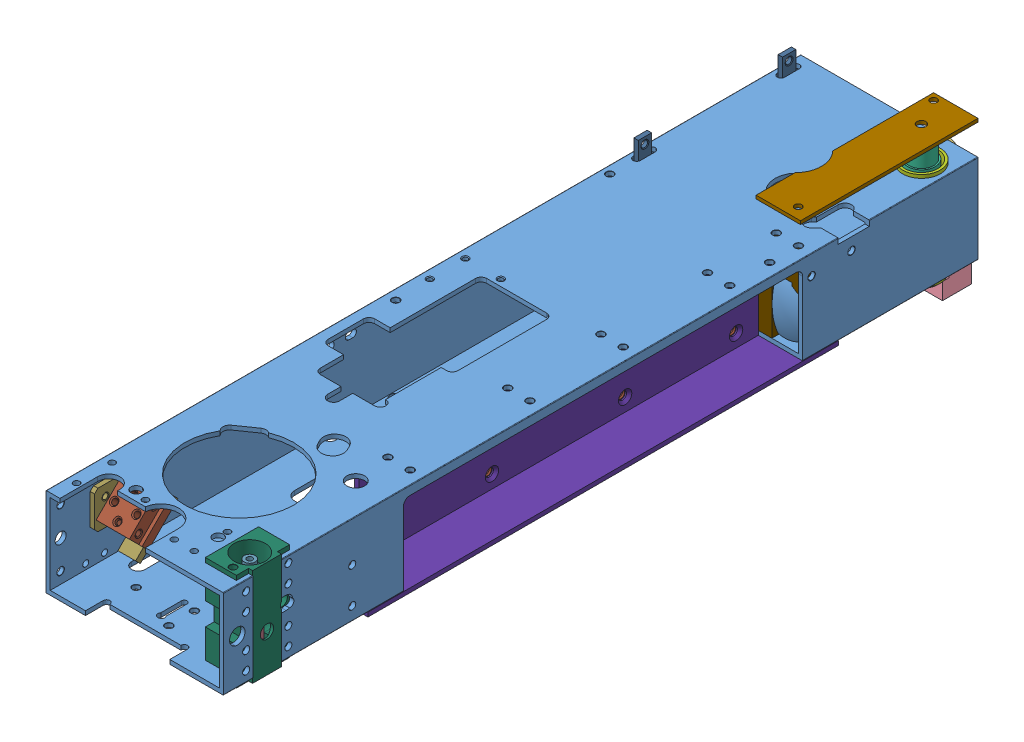
SolidWorks assembly База, configuration По умолчанию. Lengths in mm.
Overall size (100 66.2 347).
43 component instances, 32 part files, 69 mates.
Components (placement in the parent):
- короб_омб-1: короб_омб [v2] at origin size (80 40 340)
- призма_в_оправе_выходная-1: призма_в_оправе_выходная [По умолчанию] at (36.6 -18.1 -39) x (-1 0 0) z (0 0 -1) size (25.01 33.43 44.8)
  - оправа_призмы-1: оправа_призмы [Default] at (-1.5 0 6) size (25 25 36)
  - 9510170000040-1: 9510170000040 [По умолчанию] at (9.8225 13.066 21.9) x (-1 0 0) z (0 0 1) size (21.19 20 15.9)
    - 9510170000041-1: 9510170000041 [По умолчанию] at (-11.1761 -9.434 0) size (21.01 20 15.9)
    - 9510170000042-3: 9510170000042 [По умолчанию] at (-11.1775 -9.434 0.0019) size (11.8 20 15.69)
  - Линза_люк_левый-1: Линза_люк_левый [По умолчанию] at (4.5 13 38.5) x (1 0 0) z (0 -1 0) size (17 3.5 21) (hidden)
  - зеркало_11х25-1: зеркало_11х25 [Default] at (5.0962 13 26.2739) x (0 1 0) z (-0.707107 0 -0.707107) size (25 11 3)
  - зеркало_11х25-2: зеркало_11х25 [Default] at (16.9038 13 26.4588) x (0 1 0) z (0.707107 0 0.707107) size (25 11 3)
  - люк_левый_v4-1: люк_левый_v4 [По умолчанию] at (11 12.5 32.5) size (21 21 9.5)
  - Плата_с_датчиками_1-1: Плата_с_датчиками_1 [По умолчанию] at (14.5 32 -5.4093) x (-1 0 0) z (0 0 -1) size (16 6.63 32)
    - плата_датчиков_1-1: плата_датчиков_1 [По умолчанию] at origin size (16 1 32)
    - EE-SX1106-1: EE-SX1106 [По умолчанию] at (15.85 0 -10.6093) x (0 0 -1) z (0 1 0) size (8.9 4.2 6.63)
    - EE-SX1106-2: EE-SX1106 [По умолчанию] at (4.4 0 -8.6093) x (0 0 -1) z (0 1 0) size (8.9 4.2 6.63)
  - шторка_v4-1: шторка_v4 [По умолчанию] at (0.6402 3 5.3629) x (0.983937 0 -0.178516) z (0 -1 0) size (11 33.93 26.5)
- КРОНШТЕЙН5Ю-2: КРОНШТЕЙН5Ю [По умолчанию] at (-28.6 -2.8602 -33.8891) x (-1 0 0) z (0 0.707107 0.707107) size (15 16 13.5)
- зеркало_8х24-1: зеркало_8х24 [По умолчанию] at (34.1 -7.3 -29.7895) x (0 -0.707107 0.707107) z (0 0.707107 0.707107) size (24 8 3)
- зеркало_8х24-2: зеркало_8х24 [По умолчанию] at (-13.1 -7.9175 -31.6602) x (0 -0.707107 0.707107) z (0 0.707107 0.707107) size (24 8 3)
- зеркало_9х22-1: зеркало_9х22 [Default] at (32.1 -1.5 -19.7) x (0 -1 0) z (0.707107 0 0.707107) size (22 9 3)
- Бобышка зеркала-1: Бобышка зеркала [По умолчанию] at (32.1 19.5 -19.7) x (0.707107 0 -0.707107) z (0.707107 0 0.707107) size (10 17 10)
- экран_ФЭУ_2-1: экран_ФЭУ_2 [Default] at (32.1 -22 -19.7) x (0 0 -1) z (1 0 0) size (24 44.13 15.8)
- КРОНШТЕЙН9Ю-2: КРОНШТЕЙН9Ю [Default] at (24.6 11.5355 -25.9976) x (-1 0 0) z (0 1 0) size (10 14.51 12)
- отсек_кюветы_v3-1: отсек_кюветы_v3 [По умолчанию] at (18.1 -1.9 -277) x (0 -1 0) z (0 0 1) size (40 22 212)
- люк_правый_с_линзой-1: люк_правый_с_линзой [По умолчанию] at (38.1 -18.1 -261) x (-1 0 0) z (0 0 -1) size (24 36.25 8)
  - люк_правый_v3-1: люк_правый_v3 [По умолчанию] at origin size (24 36.25 8)
  - Линза_люк_правый-1: Линза_люк_правый [По умолчанию] at (9 13.25 8) x (-1 0 0) z (0 -1 0) size (12 5 26)
- подвес-1: подвес [По умолчанию] at (-3.1 -18.1 -340) size (30 36.2 8)
- шар-1: шар [По умолчанию] at (17.9 5.1 -344) x (0 1 0) z (0 0 1) size (20 20 7)
- Подвес_кюветы-1: Подвес_кюветы [По умолчанию] at (37 -20 -327) x (-1 0 0) z (0 0 1) size (77 11 13)
- вкладыш_3-1: вкладыш_3 [По умолчанию] at (-38.1 -18.1 -340) size (10 18 10)
- R6354-1: R6354 [По умолчанию] at (23.6045 21.0452 -325) x (-0.258819 0 0.965926) z (0 -1 0) size (82.45 40.02 58.7)
  - E678-11U-1: E678-11U [Default] at (-1.5259 -5.6946 -0.6548) x (0 -1 0) z (0 0 1) size (12.4 12.4 10.1)
  - ГА25301030090_ver_1-1: ГА25301030090_ver_1 [Default] at (-1.5259 -5.6946 44.5452) x (0.965926 -0.258819 0) z (0 0 1) size (17 17 45)
  - катод-1: катод [По умолчанию] at (1.8549 -6.6005 25.9452) x (0.258819 0.965926 0) z (0.965926 -0.258819 0) size (11 25 0.5)
  - плата_ФЭУ-1: плата_ФЭУ [По умолчанию] at (-18.7324 -11.9546 -14.1548) x (0.965926 -0.258819 0) z (-0.258819 -0.965926 0) size (80 1.5 20)
- планка_2хМ3_1-1: планка_2хМ3_1 [По умолчанию] at (-36.1 20 -331) x (-1 0 0) z (0 -1 0) size (2.18 6 14)
- планка_2хМ3_1-2: планка_2хМ3_1 [По умолчанию] at (-36.1 20 -266) x (-1 0 0) z (0 -1 0) size (2.18 6 14)
- планка_180-1: планка_180 [По умолчанию] at (18 -18.1 -81) x (-1 0 0) z (0 0 -1) size (9 7 180)
- катод-1: катод [По умолчанию] at (31.4671 -4.8343 -19.6845) x (0 0 1) z (-1 0 0) size (11 25 0.5) (suppressed, hidden)
- пластина_16х16-1: пластина_16х16 [По умолчанию] at (-36.1 -3.97 -35) x (0 0 1) z (-1 0 0) size (17 17 2)
- подкрепление-1: подкрепление [По умолчанию] at (-2.9 12.6 -29) (suppressed, hidden)
- втулка_2-1: втулка_2 [По умолчанию] at (8.1 -21 -80.5) x (1 0 0) z (0 -1 0) size (16 16 7.8)
- втулка_2-2: втулка_2 [По умолчанию] at (15.1 -21 -286) x (1 0 0) z (0 -1 0) size (16 16 7.8)
Mates (geometry in assembly coordinates):
- Угол2: planar angle = 3.926991 rad anti-aligned: plane of КРОНШТЕЙН5Ю-2 through (-21.1 12.3426 -30) normal (0 0.707107 0.707107); plane of короб_омб-1 through (-40 20 0) normal (0 0 1)
- Совпадение6: coincident anti-aligned: plane of зеркало_8х24-2 through (-31.6 -11.3454 -23.9896) normal (0 0.707107 0.707107); plane of КРОНШТЕЙН5Ю-2 through (-17.8791 3.5038 -38.8388) normal (0 -0.707107 -0.707107)
- Расстояние2: distance = 5 mm aligned: plane of зеркало_8х24-2 through (-31.6 -11.3454 -23.9896) normal (0 -0.707107 0.707107); plane of КРОНШТЕЙН5Ю-2 through (-21.1 1.0289 -18.6863) normal (0 -0.707107 0.707107)
- Расстояние14: distance = 0 mm anti-aligned: plane of короб_омб-1 through (-38.1 -18.1 -340) normal (0 1 0); plane of призма_в_оправе_выходная-1/оправа_призмы-1 through (13.1 -18.1 -81) normal (0 -1 0)
- Расстояние10: distance = 0 mm anti-aligned: plane of короб_омб-1 through (38.1 -18.1 -340) normal (-1 0 0); plane of призма_в_оправе_выходная-1/оправа_призмы-1 through (38.1 -18.1 -81) normal (1 0 0)
- Совпадение48: coincident anti-aligned: plane of зеркало_9х22-1 through (31.0393 9.5 -14.3967) normal (0 1 0); plane of Бобышка зеркала-1 through (24.2218 9.5 -27.5782) normal (0 -1 0)
- Совпадение46: coincident anti-aligned: plane of зеркало_9х22-1 through (35.282 9.5 -22.882) normal (-0.707107 0 -0.707107); plane of Бобышка зеркала-1 through (32.1 9.5 -19.7) normal (0.707107 0 0.707107)
- Расстояние15: distance = 0 mm aligned: plane of короб_омб-1 through (18 0 -81) normal (0 0 -1); plane of призма_в_оправе_выходная-1/оправа_призмы-1 through (38.1 -18.1 -81) normal (0 0 -1)
- Расстояние195: distance = 2 mm anti-aligned: plane of короб_омб-1 through (-38.1 -18.1 -340) normal (1 0 0); plane of КРОНШТЕЙН5Ю-2 through (-36.1 1.0289 -18.6863) normal (-1 0 0)
- Расстояние17: distance = 0.5 mm aligned: plane of зеркало_9х22-1 through (31.0393 9.5 -14.3967) normal (-0.707107 0 0.707107); cylinder of Бобышка зеркала-1 through (32.1 19.5 -19.7) axis (0 1 0) radius 5
- Ширина3: width aligned: plane of зеркало_8х24-2 through (-23.6 -11.3454 -23.9896) normal (1 0 0); plane of зеркало_8х24-2 through (-31.6 -11.3454 -23.9896) normal (-1 0 0); plane of КРОНШТЕЙН5Ю-2 through (-23.6 4.2109 -38.1317) normal (-1 0 0); plane of КРОНШТЕЙН5Ю-2 through (-31.6 4.2109 -38.1317) normal (1 0 0)
- Угол3: planar angle = 0.785398 rad aligned: plane of Бобышка зеркала-1 through (32.1 9.5 -19.7) normal (0.707107 0 0.707107); plane of короб_омб-1 through (-40 20 0) normal (0 0 1)
- Совпадение384: coincident anti-aligned: plane of короб_омб-1 through (38.1 -18.1 -340) normal (-1 0 0); plane of экран_ФЭУ_2-1 through (38.1 22 -7.7) normal (1 0 0)
- Расстояние194: distance = 2 mm aligned: plane of экран_ФЭУ_2-1 through (39.9 -22 -13.2) normal (0 -1 0); plane of короб_омб-1 through (-40 -20 -340) normal (0 -1 0)
- Ширина4: width anti-aligned: plane of экран_ФЭУ_2-1 through (38.1 22 -13.2) normal (0 0 1); plane of экран_ФЭУ_2-1 through (39.9 22 -26.2) normal (0 0 -1); plane of короб_омб-1 through (40 20 -13.2) normal (0 0 -1); plane of короб_омб-1 through (38.1 20 -26.2) normal (0 0 1)
- Совпадение385: coincident anti-aligned: plane of экран_ФЭУ_2-1 through (24.1 22 -31.7) normal (-1 0 0); plane of КРОНШТЕЙН9Ю-2 through (24.1 -0.4645 -39.9025) normal (1 0 0)
- Совпадение388: coincident anti-aligned: plane of зеркало_8х24-1 through (15.6 -10.7279 -22.1189) normal (0 0.707107 0.707107); plane of КРОНШТЕЙН9Ю-2 through (15.6 8.093 -40.9398) normal (0 -0.707107 -0.707107)
- Ширина5: width aligned: plane of зеркало_8х24-1 through (15.6 -10.7279 -22.1189) normal (-1 0 0); plane of зеркало_8х24-1 through (23.6 -10.7279 -22.1189) normal (1 0 0); plane of КРОНШТЕЙН9Ю-2 through (15.6 -3.0355 -29.8114) normal (1 0 0); plane of КРОНШТЕЙН9Ю-2 through (23.6 -3.0355 -29.8114) normal (-1 0 0)
- Совпадение389: coincident aligned: plane of зеркало_8х24-1 through (15.6 6.2426 -39.0894) normal (0 0.707107 -0.707107); plane of КРОНШТЕЙН9Ю-2 through (14.6 4.8284 -40.5037) normal (0 0.707107 -0.707107)
- Концентричный1: concentric aligned: cylinder of экран_ФЭУ_2-1 through (24.1 2 -28.2) axis (1 0 0) radius 1.5; cylinder of КРОНШТЕЙН9Ю-2 through (24.6 2 -28.2) axis (1 0 0) radius 1.25
- Ширина57: width anti-aligned: plane of короб_омб-1 through (18 0 -261) normal (0 0 1); plane of короб_омб-1 through (18 0 -81) normal (0 0 -1); plane of отсек_кюветы_v3-1 through (40.1 -1.9 -261) normal (0 0 -1); plane of отсек_кюветы_v3-1 through (40.1 -1.9 -81) normal (0 0 1)
- Совпадение245: coincident anti-aligned: plane of короб_омб-1 through (-40 -20 -340) normal (0 -1 0); plane of отсек_кюветы_v3-1 through (20 -20 -65) normal (0 1 0)
- Совпадение246: coincident anti-aligned: plane of короб_омб-1 through (38.1 -18.1 -340) normal (-1 0 0); plane of отсек_кюветы_v3-1 through (38.1 18.1 -65) normal (1 0 0)
- Совпадение416: coincident anti-aligned: plane of короб_омб-1 through (38.1 -18.1 -340) normal (-1 0 0); plane of люк_правый_с_линзой-1/люк_правый_v3-1 through (38.1 -18.1 -269) normal (1 0 0)
- Совпадение417: coincident anti-aligned: plane of короб_омб-1 through (-38.1 -18.1 -340) normal (0 1 0); plane of люк_правый_с_линзой-1/люк_правый_v3-1 through (38.1 -18.1 -269) normal (0 -1 0)
- Совпадение418: coincident anti-aligned: plane of отсек_кюветы_v3-1 through (40.1 -1.9 -261) normal (0 0 -1); plane of люк_правый_с_линзой-1/люк_правый_v3-1 through (38.1 18.15 -261) normal (0 0 1)
- Параллельность1: parallel: plane of экран_ФЭУ_2-1 through (38.1 22 -31.7) normal (0 0 -1); line of КРОНШТЕЙН9Ю-2 through (14.6 -0.4645 -25.9976) axis (0 1 0)
- Ширина65: width anti-aligned: plane of короб_омб-1 through (-38.1 -18.1 -340) normal (0 1 0); plane of короб_омб-1 through (-38.1 18.1 -340) normal (0 -1 0); plane of подвес-1 through (-3.1 -18.1 -332) normal (0 -1 0); plane of подвес-1 through (-3.1 18.1 -332) normal (0 1 0)
- Совпадение4002: coincident anti-aligned: plane of подвес-1 through (-3.1 18.1 -340) normal (0 0 -1); plane of шар-1 through (8.9 5.1 -340) normal (0 0 1)
- Совпадение290: coincident anti-aligned: plane of короб_омб-1 through (-40 -20 -340) normal (0 -1 0); plane of Подвес_кюветы-1 through (-40 -20 -327) normal (0 1 0)
- Совпадение291: coincident aligned: plane of короб_омб-1 through (-40 -20 -340) normal (-1 0 0); plane of Подвес_кюветы-1 through (-40 -31 -327) normal (-1 0 0)
- Совпадение292: coincident aligned: plane of короб_омб-1 through (-40 20 -340) normal (0 0 -1); plane of Подвес_кюветы-1 through (-40 -20 -340) normal (0 0 -1)
- Совпадение271: coincident aligned: plane of короб_омб-1 through (-40 20 -340) normal (0 0 -1); plane of вкладыш_3-1 through (-38.1 -18.1 -340) normal (0 0 -1)
- Совпадение272: coincident anti-aligned: plane of короб_омб-1 through (-38.1 -18.1 -340) normal (1 0 0); plane of вкладыш_3-1 through (-38.1 -18.1 -330) normal (-1 0 0)
- Совпадение273: coincident anti-aligned: plane of короб_омб-1 through (-38.1 -18.1 -340) normal (0 1 0); plane of вкладыш_3-1 through (-28.1 -18.1 -330) normal (0 -1 0)
- Параллельность34: parallel aligned: plane of короб_омб-1 through (-40 20 0) normal (0 0 1); plane of R6354-1/ГА25301030090_ver_1-1
- Концентрический55: concentric anti-aligned: cylinder of короб_омб-1 through (29.5 -20 -325) axis (0 1 0) radius 8.5; cylinder of R6354-1/ГА25301030090_ver_1-1 through (29.5 -23.5 -325) axis (0 -1 0) radius 8.5
- Совпадение4011: coincident anti-aligned: plane of R6354-1/ГА25301030090_ver_1-1 through (26.75 -23.5 -325) normal (0 -1 0); plane of Подвес_кюветы-1 through (-1.5 -23.5 -394.3809) normal (0 1 0)
- Совпадение4016: coincident anti-aligned: plane of короб_омб-1 through (-38.1 -18.1 -340) normal (1 0 0); plane of планка_2хМ3_1-2 through (-38.1 27 -269) normal (-1 0 0)
- Совпадение4017: coincident anti-aligned: plane of короб_омб-1 through (-38.1 -18.1 -340) normal (1 0 0); plane of планка_2хМ3_1-1 through (-38.1 27 -334) normal (-1 0 0)
- Параллельность35: parallel aligned: plane of короб_омб-1 through (-40 20 -340) normal (0 1 0); plane of планка_2хМ3_1-1 through (-38.1 27 -328) normal (0 1 0)
- Параллельность36: parallel aligned: plane of короб_омб-1 through (-40 20 -340) normal (0 1 0); plane of планка_2хМ3_1-2 through (-38.1 27 -263) normal (0 1 0)
- Концентричный1243: concentric aligned: cylinder of планка_2хМ3_1-2 through (-38.1 16 -266) axis (-1 0 0) radius 1.4224; cylinder of короб_омб-1 through (-40 16 -266) axis (-1 0 0) radius 1.6
- Концентричный1244: concentric aligned: cylinder of планка_2хМ3_1-1 through (-38.1 16 -331) axis (-1 0 0) radius 1.4224; cylinder of короб_омб-1 through (-40 16 -331) axis (-1 0 0) radius 1.6
- Концентричный1247: concentric aligned: cylinder of короб_омб-1 through (22.9 20 -337) axis (0 1 0) radius 1.6; cylinder of подвес-1 through (22.9 18.1 -337) axis (0 1 0) radius 1.25
- Совпадение4018: coincident anti-aligned: plane of короб_омб-1 through (-38.1 -18.1 -340) normal (0 1 0); plane of планка_180-1 through (18 -18.1 -261) normal (0 -1 0)
- Концентричный1249: concentric aligned: cylinder of короб_омб-1 through (13 -20 -146) axis (0 -1 0) radius 1.6; cylinder of планка_180-1 through (13 -18.1 -146) axis (0 -1 0) radius 1.25
- Параллельность37: parallel aligned: plane of короб_омб-1 through (18 0 -436.3781) normal (1 0 0); plane of планка_180-1 through (18 -18.1 -261) normal (1 0 0)
- Параллельность38: parallel aligned: plane of короб_омб-1 through (-40 20 -340) normal (0 0 -1); plane of подвес-1 through (-3.1 18.1 -340) normal (0 0 -1)
- Параллельность39: parallel anti-aligned: plane of экран_ФЭУ_2-1 through (39.9 22 -13.2) normal (1 0 0); plane of катод-1 through (30.9671 -26.2202 -19.6845) normal (-1 0 0)
- Параллельность40: parallel aligned: plane of экран_ФЭУ_2-1 through (38.1 22 -13.2) normal (0 0 1); plane of катод-1 through (30.9671 -26.2202 -14.1845) normal (0 0 1)
- Совпадение4019: coincident anti-aligned: plane of короб_омб-1 through (-38.1 -18.1 -340) normal (1 0 0); plane of пластина_16х16-1 through (-38.1 13.03 -35) normal (-1 0 0)
- Параллельность41: parallel aligned: plane of короб_омб-1 through (-40 20 0) normal (0 0 1); plane of пластина_16х16-1 through (-38.1 -2.47 -18) normal (0 0 1)
- Концентричный1250: concentric aligned: cylinder of КРОНШТЕЙН5Ю-2 through (-36.1 8.1 -30) axis (-1 0 0) radius 1.25; cylinder of пластина_16х16-1 through (-38.1 8.1 -30) axis (-1 0 0) radius 1.8
- Концентричный1251: concentric aligned: cylinder of короб_омб-1 through (-40 8.1 -22.93) axis (-1 0 0) radius 1.7; cylinder of пластина_16х16-1 through (-38.1 8.1 -22.93) axis (-1 0 0) radius 1.25
- Совпадение4669: coincident anti-aligned: plane of короб_омб-1 through (-38.1 18.1 -340) normal (0 -1 0); plane of подкрепление-1 through (-38.1 18.1 -23) normal (0 1 0)
- Совпадение4670: coincident: plane of короб_омб-1 through (-38.1 -18.1 -340) normal (1 0 0); plane of подкрепление-1 through (-38.1 7.1 -23) normal (-1 0 0)
- Расстояние237: distance = 23 mm aligned: plane of короб_омб-1 through (-40 20 0) normal (0 0 1); plane of подкрепление-1 through (32.3 18.1 -23) normal (0 0 1)
- Совпадение4678: coincident anti-aligned: plane of короб_омб-1 through (-38.1 -18.1 -340) normal (1 0 0); plane of подкрепление-1 through (-38.1 7.1 -23) normal (-1 0 0)
- Совпадение4611: coincident anti-aligned: plane of короб_омб-1 through (-40 -20 -340) normal (0 -1 0); plane of втулка_2-1 through (8.1 -20 -73.5) normal (0 1 0)
- Совпадение4610: coincident anti-aligned: plane of короб_омб-1 through (-40 -20 -340) normal (0 -1 0); plane of втулка_2-2 through (15.1 -20 -279) normal (0 1 0)
- Концентричный1252: concentric aligned: cylinder of короб_омб-1 through (8.1 20.001 -80.5) axis (0 -1 0) radius 7; cylinder of втулка_2-1 through (8.1 -21 -80.5) axis (0 -1 0) radius 7
- Концентричный1253: concentric aligned: cylinder of короб_омб-1 through (15.1 20.001 -286) axis (0 -1 0) radius 7; cylinder of втулка_2-2 through (15.1 -21 -286) axis (0 -1 0) radius 7
- Параллельность42: parallel aligned: plane of короб_омб-1 through (40 -20 -340) normal (1 0 0); plane of втулка_2-1
- Параллельность43: parallel aligned: plane of короб_омб-1 through (40 -20 -340) normal (1 0 0); plane of втулка_2-2
- Параллельность44: parallel anti-aligned: plane of короб_омб-1 through (40 -20 -340) normal (1 0 0); plane of шар-1
- Концентричный1254: concentric aligned: cylinder of подвес-1 through (17.9 11.1 -340) axis (0 0 -1) radius 1.25; cylinder of шар-1 through (17.9 11.1 -347) axis (0 0 -1) radius 1.7
- Концентричный1255: concentric aligned: cylinder of Бобышка зеркала-1 through (32.1 19.5 -19.7) axis (0 1 0) radius 2.5; cylinder of экран_ФЭУ_2-1 through (32.1 -41.799 -19.7) axis (0 1 0) radius 7
- Расстояние238: distance = 7 mm aligned: plane of экран_ФЭУ_2-1 through (39.9 22 -13.2) normal (0 1 0); plane of Бобышка зеркала-1 through (30.3322 15 -21.4678) normal (0 1 0)
